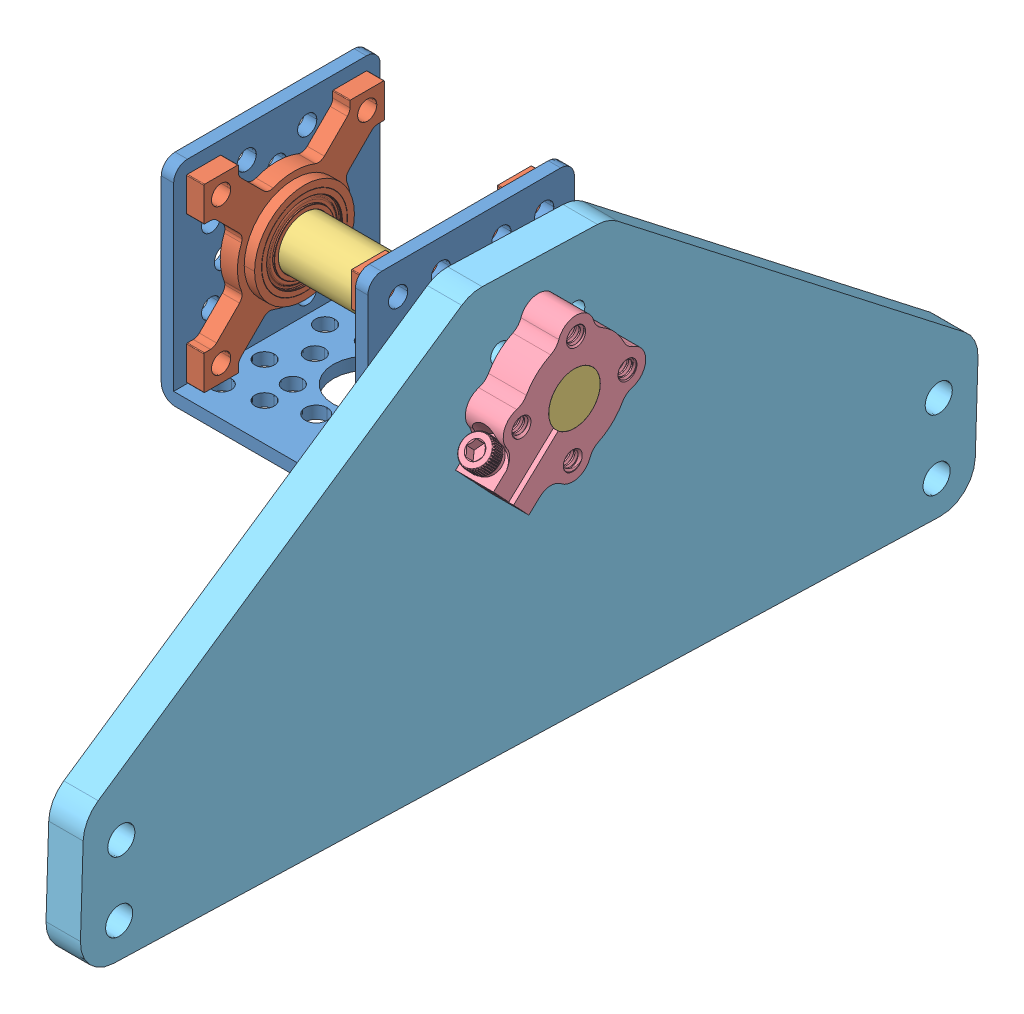
SolidWorks assembly Suspension Pivot Assem, configuration Default. Lengths in mm.
Overall size (63.5 81.39 167.43).
6 component instances, 5 part files, 14 mates.
Components (placement in the parent):
- 1.5in c channel-1: 1.5in c channel [Default] at origin size (38.1 38.1 38.1)
- 3-8in pillow block bearing 535114 -1: 3-8in pillow block bearing 535114  [Default] at (-11.8236 28.513 -8.5366) x (0 -1 0) z (0 0 1) size (33.27 5.09 33.27)
- 3-8in pillow block bearing 535114 -3: 3-8in pillow block bearing 535114  [Default] at (49.9236 28.513 46.6366) x (0 -1 0) z (0 0 -1) size (33.27 5.09 33.27)
- .375in shaft for suspension-1: .375in shaft for suspension [Default] at (57.15 19.05 19.05) x (0 0.99611 0.088123) z (-1 0 0) size (9.53 9.53 63.5)
- .375in clamping hub 545596-1: .375in clamping hub 545596 [Default] at (37.5726 39.3529 58.193) x (0 0.729135 0.68437) z (0 0.68437 -0.729135) size (20.57 9.53 26.29)
- Back connector for suspension-1: Back connector for suspension [Default] at (43.815 0.0095 19.653) x (0 0.031654 0.999499) z (1 0 0) size (165.1 76.2 6.35)
Mates (geometry in assembly coordinates):
- Coincident1: coordinate: point of 1.5in c channel-1
- Concentric1: concentric aligned: cylinder of 1.5in c channel-1 through (38.1 32.5204 5.5796) axis (1 0 0) radius 1.778; cylinder of 3-8in pillow block bearing 535114 -1 through (5.461 32.5204 5.5796) axis (1 0 0) radius 1.778
- Concentric2: concentric aligned: cylinder of 1.5in c channel-1 through (38.1 32.5204 32.5204) axis (1 0 0) radius 1.778; cylinder of 3-8in pillow block bearing 535114 -1 through (5.461 32.5204 32.5204) axis (1 0 0) radius 1.778
- Coincident2: coincident anti-aligned: plane of 1.5in c channel-1 through (2.286 38.1 38.1) normal (1 0 0); plane of 3-8in pillow block bearing 535114 -1 through (2.286 19.05 19.05) normal (-1 0 0)
- Concentric3: concentric anti-aligned: cylinder of 1.5in c channel-1 through (38.1 32.5204 5.5796) axis (1 0 0) radius 1.778; cylinder of 3-8in pillow block bearing 535114 -3 through (32.639 32.5204 5.5796) axis (-1 0 0) radius 1.778
- Concentric4: concentric anti-aligned: cylinder of 1.5in c channel-1 through (38.1 32.5204 32.5204) axis (1 0 0) radius 1.778; cylinder of 3-8in pillow block bearing 535114 -3 through (32.639 32.5204 32.5204) axis (-1 0 0) radius 1.778
- Coincident3: coincident anti-aligned: plane of 1.5in c channel-1 through (35.814 2.286 38.1) normal (-1 0 0); plane of 3-8in pillow block bearing 535114 -3 through (35.814 19.05 19.05) normal (1 0 0)
- Concentric5: concentric anti-aligned: cylinder of 3-8in pillow block bearing 535114 -1 through (7.3723 19.05 19.05) axis (-1 0 0) radius 4.7625; cylinder of .375in shaft for suspension-1 through (-6.35 19.05 19.05) axis (1 0 0) radius 4.7625
- Distance1: distance = 6.35 mm aligned: plane of .375in shaft for suspension-1 through (-6.35 19.05 19.05) normal (-1 0 0); plane of 1.5in c channel-1 through (0 0 38.1) normal (-1 0 0)
- Concentric6: concentric anti-aligned: cylinder of .375in shaft for suspension-1 through (-6.35 19.05 19.05) axis (1 0 0) radius 4.7625; cylinder of Back connector for suspension-1 through (50.165 19.05 19.05) axis (-1 0 0) radius 6.35
- Concentric7: concentric anti-aligned: cylinder of .375in shaft for suspension-1 through (-6.35 19.05 19.05) axis (1 0 0) radius 4.7625; cylinder of .375in clamping hub 545596-1 through (47.625 19.05 19.05) axis (-1 0 0) radius 4.7625
- Concentric8: concentric aligned: circle of .375in clamping hub 545596-1; circle of Back connector for suspension-1
- Coincident5: coincident anti-aligned: plane of .375in clamping hub 545596-1 through (50.165 19.05 19.05) normal (-1 0 0); plane of Back connector for suspension-1 through (50.165 0.0095 19.653) normal (1 0 0)
- Coincident6: coincident aligned: plane of .375in shaft for suspension-1 through (57.15 19.05 19.05) normal (1 0 0); plane of .375in clamping hub 545596-1 through (57.15 19.05 19.05) normal (1 0 0)
